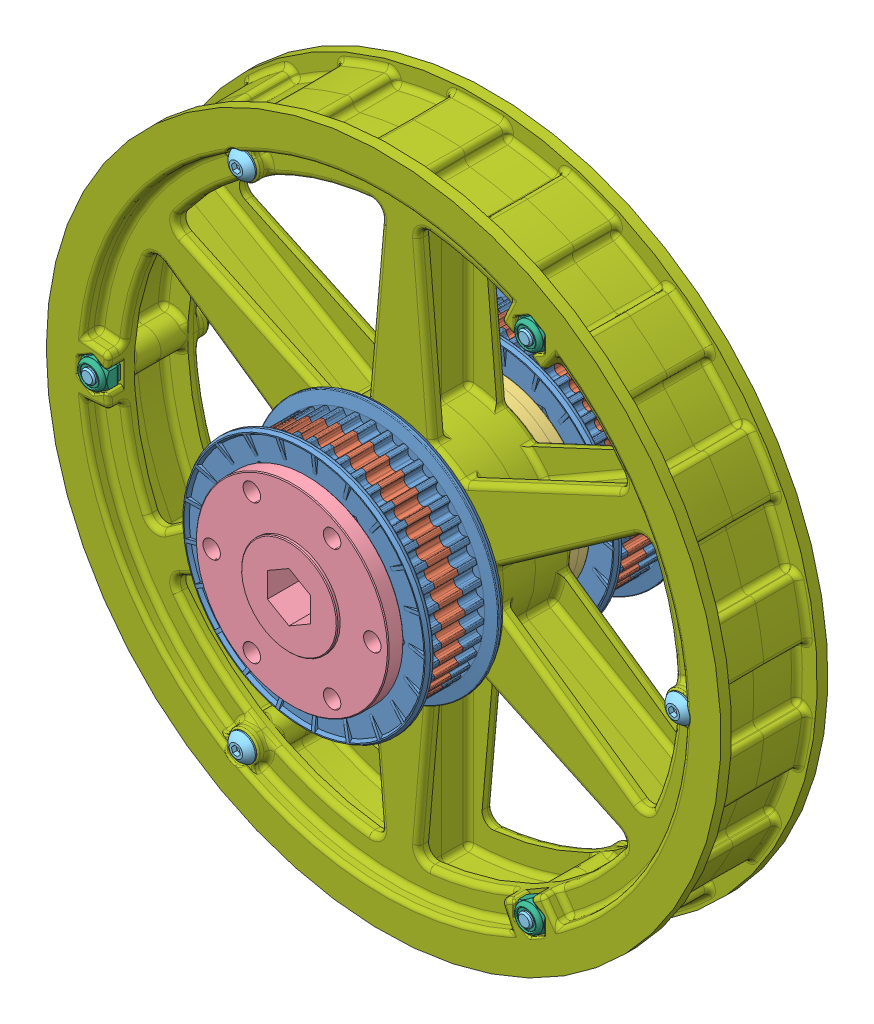
SolidWorks assembly Wheel Drive Fixed 2.1, configuration 8in Wheel. Lengths in mm.
Overall size (273.24 273.24 87.85).
56 component instances, 11 part files, 30 mates.
Components (placement in the parent):
- 217-2589 1in.20121203-1: 217-2589 1in.20121203 [Default] at origin size (158.75 158.75 36.2) (suppressed, hidden)
  - 217-2589-001 Rev3-1: 217-2589-001 Rev3 [Default] at origin size (149.22 149.22 19.81)
  - 217-2589-001 Rev3-2: 217-2589-001 Rev3 [Default] x (-1 0 0) z (0 0 -1) size (149.22 149.22 19.81)
  - SCREW-832-1250-1: SCREW-832-1250 [Default] at (60.96 0 -15.8623) x (0 0 1) z (-1 0 0) size (33.96 7.92 7.92)
  - NUT-832-NYLOCK-1: NUT-832-NYLOCK [Default] at (60.96 0 12.0688) x (0.866025 0.5 0) z (0.5 -0.866025 0) size (10.2 5.86 8.12)
  - BEAM-0750-1: BEAM-0750 [Default] at (11.9062 -20.6222 0.0635) x (0.866025 0.5 0) z (-0.5 0.866025 0) size (7.34 19.93 7.34)
  - BEAM-0750-2: BEAM-0750 [Default] at (-11.9062 -20.6222 0.0635) x (0.866025 -0.5 0) z (0.5 0.866025 0) size (7.34 19.93 7.34)
  - BEAM-0750-3: BEAM-0750 [Default] at (-23.8125 0 0.0635) x (0 -1 0) z (1 0 0) size (7.34 19.93 7.34)
  - BEAM-0750-4: BEAM-0750 [Default] at (-11.9062 20.6222 0.0635) x (-0.866025 -0.5 0) z (0.5 -0.866025 0) size (7.34 19.93 7.34)
  - BEAM-0750-5: BEAM-0750 [Default] at (11.9062 20.6222 0.0635) x (-0.866025 0.5 0) z (-0.5 -0.866025 0) size (7.34 19.93 7.34)
  - BEAM-0750-6: BEAM-0750 [Default] at (23.8125 0 0.0635) x (0 1 0) z (-1 0 0) size (7.34 19.93 7.34)
  - SCREW-832-1250-2: SCREW-832-1250 [Default] at (30.48 52.7929 15.8623) x (0 0 -1) z (0.923728 0.383049 0) size (33.96 7.92 7.92)
  - NUT-832-NYLOCK-2: NUT-832-NYLOCK [Default] at (30.48 52.7929 -12.0688) x (-0.866025 -0.5 0) z (0.5 -0.866025 0) size (10.2 5.86 8.12)
  - NUT-832-NYLOCK-3: NUT-832-NYLOCK [Default] at (30.48 -52.7929 -12.0688) x (0 1 0) z (-1 0 0) size (10.2 5.86 8.12)
  - NUT-832-NYLOCK-4: NUT-832-NYLOCK [Default] at (-60.96 0 -12.0688) x (0.866025 -0.5 0) z (0.5 0.866025 0) size (10.2 5.86 8.12)
  - SCREW-832-1250-3: SCREW-832-1250 [Default] at (-30.48 -52.7929 -15.8623) x (0 0 1) z (0.5 0.866025 0) size (33.96 7.92 7.92)
  - SCREW-832-1250-4: SCREW-832-1250 [Default] at (-30.48 52.7929 -15.8623) x (0 0 1) z (0.5 -0.866025 0) size (33.96 7.92 7.92)
  - NUT-832-NYLOCK-5: NUT-832-NYLOCK [Default] at (-30.48 -52.7929 12.0688) x (0 -1 0) z (-1 0 0) size (10.2 5.86 8.12)
  - NUT-832-NYLOCK-6: NUT-832-NYLOCK [Default] at (-30.48 52.7929 12.0688) x (-0.866025 0.5 0) z (0.5 0.866025 0) size (10.2 5.86 8.12)
  - SCREW-832-1250-5: SCREW-832-1250 [Default] at (30.48 -52.7929 15.8623) x (0 0 -1) z (-0.130134 -0.991496 0) size (33.96 7.92 7.92)
  - SCREW-832-1250-6: SCREW-832-1250 [Default] at (-60.96 0 15.8623) x (0 0 -1) z (-0.793594 0.608447 0) size (33.96 7.92 7.92)
  - 217-2860-001 Rev3-1: 217-2860-001 Rev3 [Default] at (0 0 -6.35) size (158.75 158.75 12.71)
  - 217-2860-001 Rev3-2: 217-2860-001 Rev3 [Default] at (0 0 6.35) size (158.75 158.75 12.71)
- 217-3199-STEP-1: 217-3199-STEP [Default] at (0 0 36.875) x (0 -1 0) z (0 0 1) size (73 73 23.01)
  - 217-3199-001 Rev4-1: 217-3199-001 Rev4 [Default] at origin size (73 73 11.51)
  - 217-3199-001 Rev4-2: 217-3199-001 Rev4 [Default] at (0 0 -17.825) x (-1 0 0) z (0 0 -1) size (73 73 11.51)
  - 217-3199-002 Rev3-1: 217-3199-002 Rev3 [Default] at (0 0 -5.5) x (-1 0 0) z (0 0 1) size (65.74 65.61 14)
- 217-3199-STEP-2: 217-3199-STEP [Default] at (0 0 -19.05) x (0 -1 0) z (0 0 1) size (73 73 23.01)
  - 217-3199-001 Rev4-1: 217-3199-001 Rev4 [Default] at origin size (73 73 11.51)
  - 217-3199-001 Rev4-2: 217-3199-001 Rev4 [Default] at (0 0 -17.825) x (-1 0 0) z (0 0 -1) size (73 73 11.51)
  - 217-3199-002 Rev3-1: 217-3199-002 Rev3 [Default] at (0 0 -5.5) x (-1 0 0) z (0 0 1) size (65.74 65.61 14)
- 217-3234-STEP-1: 217-3234-STEP [Default] at (0 0 14.2875) x (0.866025 0.5 0) z (0.5 -0.866025 0)
- 217-3234-STEP-2: 217-3234-STEP [Default] at (0 0 -14.2875) x (0.866025 0.5 0) z (-0.5 0.866025 0)
- 500 Hex Hub (am-0096a)-1: 500 Hex Hub (am-0096a) [Default] at (0 0 24.5384) x (0 0 -1) z (-0.5 0.866025 0)
- 500 Hex Hub (am-0096a)-2: 500 Hex Hub (am-0096a) [Default] at (0 0 -24.5384) x (0 0 1) z (0.5 0.866025 0)
- 217-2605 1in.20121203-2: 217-2605 1in.20121203 [Default] at origin size (273.24 273.24 34.92)
  - SBS1_SBS0832-1250SS-1: SBS1_SBS0832-1250SS [Default] at (-86.36 0 -16.4973) x (0 0 1) z (0.950435 -0.310923 0) size (34.41 8.02 7.99)
  - SBS1_SBS0832-1250SS-2: SBS1_SBS0832-1250SS [Default] at (-43.18 74.79 16.4973) x (0 0 -1) z (-0.955409 -0.295284 0) size (34.41 8.02 7.99)
  - NUT-832-NYLOCK-1: NUT-832-NYLOCK [Default] at (-86.36 0 12.0688) x (0.866025 0.5 0) z (0.5 -0.866025 0) size (10.2 5.86 8.12)
  - NUT-832-NYLOCK-2: NUT-832-NYLOCK [Default] at (-43.18 74.79 -12.0688) x (-0.866025 -0.5 0) z (0.5 -0.866025 0) size (10.2 5.86 8.12)
  - 217-2605-001 Rev1-1: 217-2605-001 Rev1 [Default] x (-0.5 0.866025 0) z (0 0 1) size (200.03 200.03 19.71)
  - 217-2605-001 Rev1-2: 217-2605-001 Rev1 [Default] x (-1 0 0) z (0 0 -1) size (200.03 200.03 19.71)
  - NUT-832-NYLOCK-3: NUT-832-NYLOCK [Default] at (86.36 0 -12.0688) x (0 1 0) z (-1 0 0) size (10.2 5.86 8.12)
  - NUT-832-NYLOCK-4: NUT-832-NYLOCK [Default] at (-43.18 -74.79 -12.0688) x (0.866025 -0.5 0) z (0.5 0.866025 0) size (10.2 5.86 8.12)
  - NUT-832-NYLOCK-5: NUT-832-NYLOCK [Default] at (43.18 74.79 12.0688) x (0 -1 0) z (-1 0 0) size (10.2 5.86 8.12)
  - NUT-832-NYLOCK-6: NUT-832-NYLOCK [Default] at (43.18 -74.79 12.0688) x (-0.866025 0.5 0) z (0.5 0.866025 0) size (10.2 5.86 8.12)
  - SBS1_SBS0832-1250SS-3: SBS1_SBS0832-1250SS [Default] at (43.18 74.79 -16.4973) x (0 0 1) z (-0.744485 -0.66764 0) size (34.41 8.02 7.99)
  - SBS1_SBS0832-1250SS-4: SBS1_SBS0832-1250SS [Default] at (43.18 -74.79 -16.4973) x (0 0 1) z (-0.20595 0.978562 0) size (34.41 8.02 7.99)
  - SBS1_SBS0832-1250SS-5: SBS1_SBS0832-1250SS [Default] at (86.36 0 16.4973) x (0 0 -1) z (0.221981 0.975051 0) size (34.41 8.02 7.99)
  - SBS1_SBS0832-1250SS-6: SBS1_SBS0832-1250SS [Default] at (-43.18 -74.79 16.4973) x (0 0 -1) z (0.733429 -0.679767 0) size (34.41 8.02 7.99)
  - BEAM-0750-1: BEAM-0750 [Default] at (-23.8125 0 0) x (0.866025 0.5 0) z (-0.5 0.866025 0) size (7.34 19.93 7.34)
  - BEAM-0750-2: BEAM-0750 [Default] at (-11.9062 20.6222 0) x (0.866025 -0.5 0) z (0.5 0.866025 0) size (7.34 19.93 7.34)
  - BEAM-0750-3: BEAM-0750 [Default] at (11.9062 20.6222 0) x (0 -1 0) z (1 0 0) size (7.34 19.93 7.34)
  - BEAM-0750-4: BEAM-0750 [Default] at (23.8125 0 0) x (-0.866025 -0.5 0) z (0.5 -0.866025 0) size (7.34 19.93 7.34)
  - BEAM-0750-5: BEAM-0750 [Default] at (11.9062 -20.6222 0) x (-0.866025 0.5 0) z (-0.5 -0.866025 0) size (7.34 19.93 7.34)
  - BEAM-0750-6: BEAM-0750 [Default] at (-11.9062 -20.6222 0) x (0 1 0) z (-1 0 0) size (7.34 19.93 7.34)
Mates (geometry in assembly coordinates):
- Concentric1: concentric anti-aligned: cylinder of 217-2589 1in.20121203-1/217-2589-001 Rev3-2 through (0 0 11.1125) axis (0 0 -1) radius 14.3; cylinder of 217-3199-STEP-1/217-3199-001 Rev4-2 through (0 0 17.4625) axis (0 0 1) radius 14.3
- Concentric2: concentric anti-aligned: cylinder of 217-3234-STEP-1 through (-11.9062 -20.6222 14.2875) axis (0 0 -1) radius 2.1526; cylinder of 217-3199-STEP-1/217-3199-002 Rev3-1 through (-11.9062 -20.6222 29.7875) axis (0 0 1) radius 2.1526
- Coincident2: coincident anti-aligned: plane of 217-3234-STEP-2 through (0 0 -17.4625) normal (0 0 -1); plane of 217-3199-STEP-2/217-3199-001 Rev4-1 through (0 0 -17.4625) normal (0 0 1)
- Concentric3: concentric anti-aligned: cylinder of 217-2589 1in.20121203-1/217-2589-001 Rev3-1 through (0 0 -11.1125) axis (0 0 1) radius 14.3; cylinder of 217-3199-STEP-2/217-3199-001 Rev4-1 through (0 0 -17.4625) axis (0 0 -1) radius 14.3
- Concentric4: concentric: cylinder of 217-3199-STEP-2/217-3199-001 Rev4-1 through (-23.8125 0 -20.6375) axis (0 0 1) radius 2.1526; cylinder of 217-2589 1in.20121203-1/217-2589-001 Rev3-1 through (-23.8125 0 -7.9375) axis (0 0 -1) radius 2.1526
- Concentric5: concentric anti-aligned: cylinder of 217-2589 1in.20121203-1/217-2589-001 Rev3-2 through (0 0 11.1125) axis (0 0 -1) radius 14.3; cylinder of 217-3234-STEP-1 through (0 0 11.1125) axis (0 0 1) radius 14.3
- Concentric6: concentric anti-aligned: cylinder of 217-2589 1in.20121203-1/217-2589-001 Rev3-2 through (-11.9062 20.6222 7.9375) axis (0 0 1) radius 2.1526; cylinder of 217-3234-STEP-1 through (-11.9062 20.6222 14.2875) axis (0 0 -1) radius 2.1526
- Coincident3: coincident aligned: plane of 217-2589 1in.20121203-1/217-2589-001 Rev3-2 through (0 0 11.1125) normal (0 0 -1); plane of 217-3234-STEP-1 through (0 0 11.1125) normal (0 0 -1)
- Coincident4: coincident anti-aligned: plane of 217-3199-STEP-1/217-3199-001 Rev4-2 through (0 0 17.4625) normal (0 0 -1); plane of 217-3234-STEP-1 through (0 0 17.4625) normal (0 0 1)
- Concentric7: concentric anti-aligned: cylinder of 217-2589 1in.20121203-1/217-2589-001 Rev3-1 through (0 0 -11.1125) axis (0 0 1) radius 14.3; cylinder of 217-3234-STEP-2 through (0 0 -11.1125) axis (0 0 -1) radius 14.3
- Concentric8: concentric anti-aligned: cylinder of 217-2589 1in.20121203-1/217-2589-001 Rev3-1 through (11.9062 20.6222 -7.9375) axis (0 0 -1) radius 2.1526; cylinder of 217-3234-STEP-2 through (11.9062 20.6222 -14.2875) axis (0 0 1) radius 2.1526
- Coincident5: coincident aligned: plane of 217-2589 1in.20121203-1/217-2589-001 Rev3-1 through (0 0 -11.1125) normal (0 0 1); plane of 217-3234-STEP-2 through (0 0 -11.1125) normal (0 0 1)
- Concentric9: concentric anti-aligned: cylinder of 217-3199-STEP-1/217-3199-001 Rev4-1 through (0 0 38.4625) axis (0 0 -1) radius 14.3; cylinder of 500 Hex Hub (am-0096a)-1 through (0 0 18.5235) axis (0 0 1) radius 12.1666
- Coincident6: coincident anti-aligned: plane of 217-3199-STEP-1/217-3199-001 Rev4-1 through (0 0 38.4625) normal (0 0 1); plane of 500 Hex Hub (am-0096a)-1 through (-24.7467 -14.2875 38.4625) normal (0 0 -1)
- Concentric10: concentric aligned: cylinder of 217-3199-STEP-1/217-3199-002 Rev3-1 through (-23.8125 0 29.7875) axis (0 0 1) radius 2.1526; cylinder of 500 Hex Hub (am-0096a)-1 through (-23.8125 0 43.0345) axis (0 0 1) radius 2.5908
- Concentric11: concentric anti-aligned: cylinder of 217-3199-STEP-2/217-3199-001 Rev4-2 through (0 0 -38.4625) axis (0 0 1) radius 14.3; cylinder of 500 Hex Hub (am-0096a)-2 through (0 0 -18.5235) axis (0 0 -1) radius 12.1666
- Coincident7: coincident anti-aligned: plane of 217-3199-STEP-2/217-3199-001 Rev4-2 through (0 0 -38.4625) normal (0 0 -1); plane of 500 Hex Hub (am-0096a)-2 through (24.7467 -14.2875 -38.4625) normal (0 0 1)
- Concentric12: concentric aligned: cylinder of 217-3199-STEP-2/217-3199-001 Rev4-2 through (11.9062 -20.6222 -35.2875) axis (0 0 -1) radius 2.1526; cylinder of 500 Hex Hub (am-0096a)-2 through (11.9062 -20.6222 -43.0345) axis (0 0 -1) radius 2.5908
- Coincident8: coincident aligned: plane of 217-2589 1in.20121203-1/217-2589-001 Rev3-1 through (0 0 0) normal (0 0 1); plane of assembly through (0 0 0) normal (0 0 1)
- Coincident9: coincident aligned: plane of 217-2589 1in.20121203-1/217-2589-001 Rev3-1 through (0 0 0) normal (0 1 0); plane of assembly through (0 0 0) normal (0 1 0)
- Coincident10: coincident aligned: plane of 217-2589 1in.20121203-1/217-2589-001 Rev3-1 through (0 0 0) normal (1 0 0); plane of assembly through (0 0 0) normal (1 0 0)
- Concentric13: concentric anti-aligned: cylinder of 217-3234-STEP-1 through (0 0 11.1125) axis (0 0 1) radius 14.3; cylinder of 217-2605 1in.20121203-2/217-2605-001 Rev1-2 through (0 0 11.1125) axis (0 0 -1) radius 14.3
- Concentric14: concentric anti-aligned: cylinder of 217-3234-STEP-1 through (11.9062 20.6222 14.2875) axis (0 0 -1) radius 2.1526; cylinder of 217-2605 1in.20121203-2/217-2605-001 Rev1-2 through (11.9062 20.6222 7.9375) axis (0 0 1) radius 2.1526
- Coincident11: coincident anti-aligned: plane of 217-3234-STEP-1 through (0 0 11.1125) normal (0 0 -1); plane of 217-2605 1in.20121203-2/217-2605-001 Rev1-2 through (0 0 11.1125) normal (0 0 1)
- Concentric15: concentric anti-aligned: cylinder of 217-3234-STEP-2 through (0 0 -11.1125) axis (0 0 -1) radius 14.3; cylinder of 217-2605 1in.20121203-2/217-2605-001 Rev1-1 through (0 0 -11.1125) axis (0 0 1) radius 14.3
- Concentric16: concentric anti-aligned: cylinder of 217-3234-STEP-2 through (23.8125 0 -14.2875) axis (0 0 1) radius 2.1526; cylinder of 217-2605 1in.20121203-2/217-2605-001 Rev1-1 through (23.8125 0 -7.9375) axis (0 0 -1) radius 2.1526
- Coincident12: coincident anti-aligned: plane of 217-3234-STEP-2 through (0 0 -11.1125) normal (0 0 1); plane of 217-2605 1in.20121203-2/217-2605-001 Rev1-1 through (0 0 -11.1125) normal (0 0 -1)
- Concentric17: concentric aligned: cylinder of 217-3199-STEP-2/217-3199-001 Rev4-1 through (0 0 -17.4625) axis (0 0 -1) radius 14.3; cylinder of 217-3234-STEP-2 through (0 0 -11.1125) axis (0 0 -1) radius 14.3
- Concentric18: concentric aligned: cylinder of 217-3199-STEP-2/217-3199-001 Rev4-1 through (-11.9062 20.6222 -20.6375) axis (0 0 1) radius 2.1526; cylinder of 217-3234-STEP-2 through (-11.9062 20.6222 -14.2875) axis (0 0 1) radius 2.1526
- Concentric19: concentric aligned: cylinder of 217-3199-STEP-1/217-3199-001 Rev4-2 through (0 0 17.4625) axis (0 0 1) radius 14.3; cylinder of 217-3234-STEP-1 through (0 0 11.1125) axis (0 0 1) radius 14.3
